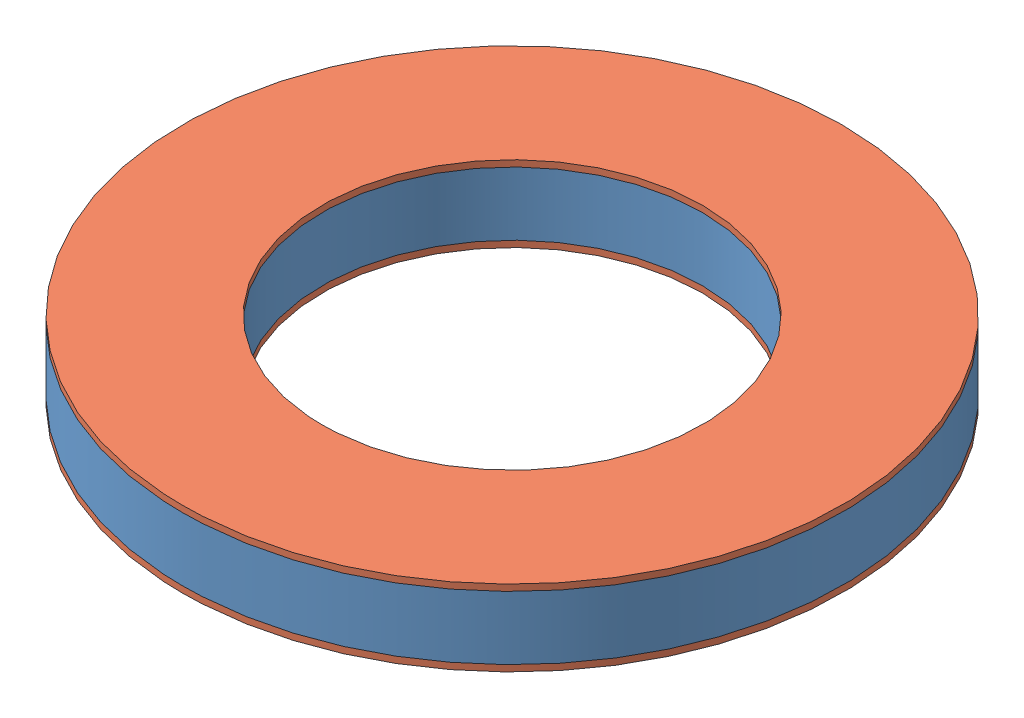
SolidWorks assembly Assem2, configuration Default. Lengths in mm.
Overall size (132.08 15.24 132.08).
3 component instances, 2 part files, 4 mates.
Components (placement in the parent):
- CenteriongRing-1: CenteriongRing [Default] at (-158.3103 8.4727 73.4679) size (132.08 12.7 132.08)
- CarbonCenteringRing-1: CarbonCenteringRing [Default] at (-158.3103 21.1727 73.4679) size (132.08 1.27 132.08)
- CarbonCenteringRing-2: CarbonCenteringRing [Default] at (-158.3103 7.2027 73.4679) size (132.08 1.27 132.08)
Mates (geometry in assembly coordinates):
- Coincident1: coincident anti-aligned: plane of CenteriongRing-1 through (-158.3103 21.1727 73.4679) normal (0 1 0); plane of CarbonCenteringRing-1 through (-158.3103 21.1727 73.4679) normal (0 -1 0)
- Coincident2: coincident anti-aligned: plane of CenteriongRing-1 through (-158.3103 8.4727 73.4679) normal (0 -1 0); plane of CarbonCenteringRing-2 through (-158.3103 8.4727 73.4679) normal (0 1 0)
- Concentric1: concentric aligned: circle of CarbonCenteringRing-1; circle of CarbonCenteringRing-2
- Concentric2: concentric aligned: circle of CenteriongRing-1; circle of CarbonCenteringRing-1
